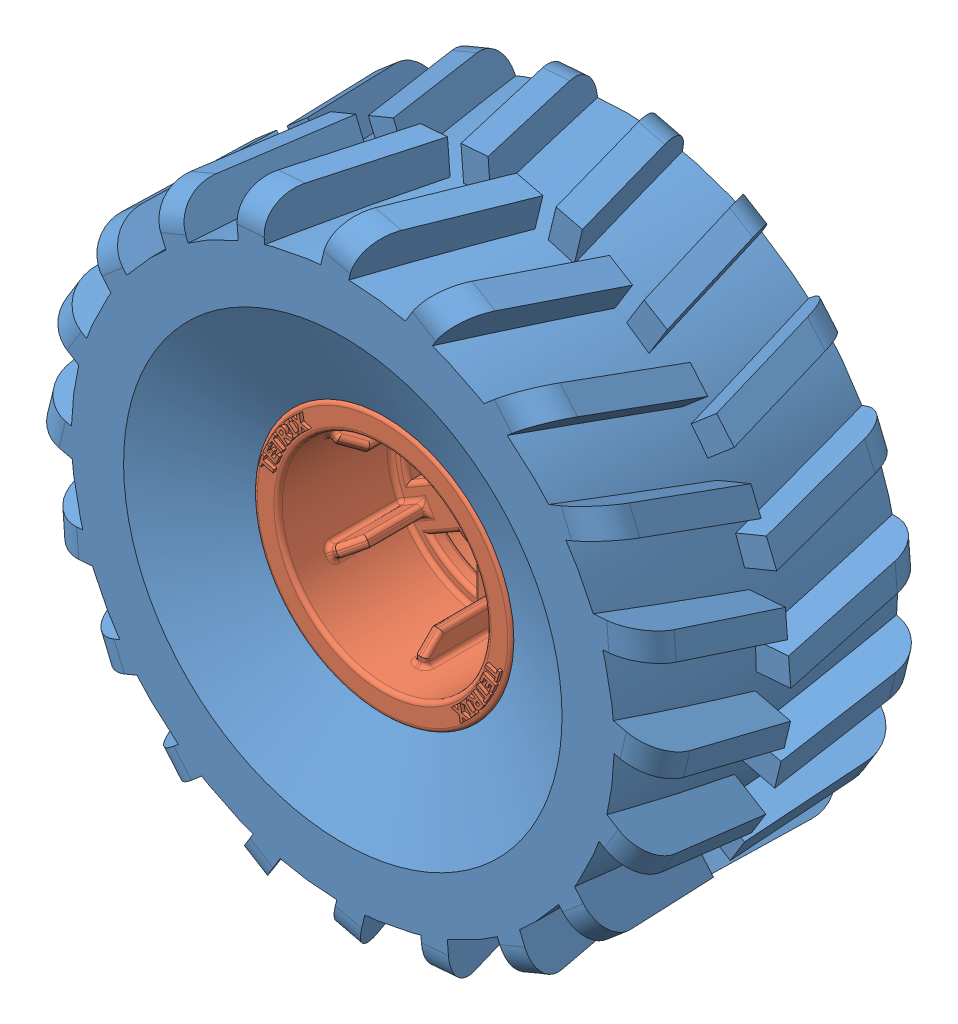
SolidWorks assembly Tetrix Wheel All Terrain, configuration Default. Lengths in mm.
Overall size (151.45 151.45 71.55).
3 component instances, 3 part files, 0 mates.
Components (placement in the parent):
- Tetrix Wheel All Terrain Tire-1: Tetrix Wheel All Terrain Tire [Default] at origin size (151.45 151.45 68.1)
- Tetrix Wheel All Terrain Hub-1: Tetrix Wheel All Terrain Hub [Default] at origin size (62 62 49.8)
- Tetrix Wheel All Terrain Axle Hub-1: Tetrix Wheel All Terrain Axle Hub [Default] at (0 0 -25.5) size (16 16 28)
